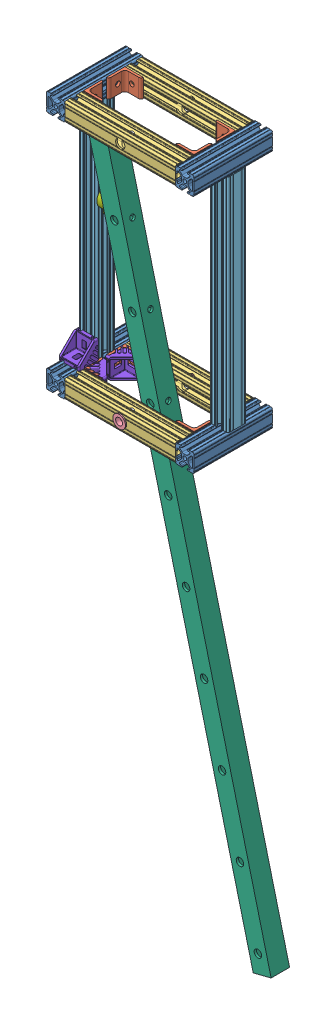
SolidWorks assembly assy_test_stand_8020, configuration Default. Lengths in mm.
Overall size (269.08 950.51 111.12).
28 component instances, 8 part files, 23 mates.
Components (placement in the parent):
- Base-1: Base [Default] at (-12.7 12.7 -79.4303) size (203.2 25.4 107.95)
  - prt_8020_1003_4.25in-1: prt_8020_1003_4.25in [Default] at origin size (25.4 25.4 107.95)
  - prt_8020_Lbracket_1x1-1: prt_8020_Lbracket_1x1 [Default] at (188.573 12.7 -96.9464) x (-1 0 0) z (0 -1 0) size (25.4 25.4 25.4)
  - prt_8020_Lbracket_1x1-2: prt_8020_Lbracket_1x1 [Default] at (39.7964 -12.7 -150.473) x (0 0 1) z (0 1 0) size (25.4 25.4 25.4)
  - prt_8020_Lbracket_1x1-3: prt_8020_Lbracket_1x1 [Default] at (188.573 -12.7 -99.9036) x (-1 0 0) z (0 1 0) size (25.4 25.4 25.4)
  - prt_8020_Lbracket_1x1-4: prt_8020_Lbracket_1x1 [Default] at (-10.773 -12.7 -96.9464) x (1 0 0) z (0 1 0) size (25.4 25.4 25.4)
  - prt_8020_1003_6in-1: prt_8020_1003_6in [Default] at (12.7 0 -139.7) x (0 0 1) z (-1 0 0) size (25.4 25.4 152.4)
  - prt_8020_1003_6in-2: prt_8020_1003_6in [Default] at (165.1 0 -57.15) x (0 0 -1) z (1 0 0) size (25.4 25.4 152.4)
  - prt_8020_1003_4.25in-2: prt_8020_1003_4.25in [Default] at (177.8 0 0) x (-1 0 0) z (0 0 1) size (25.4 25.4 107.95)
- Arms_risers-1: Arms_risers [Default] at (76.2 12.7 -245.0562) x (1 0 0) z (0 1 0) size (267.96 111.12 925.11)
  - prt_sleeve_bearing_0.375x.25-1: prt_sleeve_bearing_0.375x.25 [Default] at origin size (17.46 6.35 17.46)
  - prt_sleeve_bearing_0.375x.25-2: prt_sleeve_bearing_0.375x.25 [Default] at (0 -134.4017 0) x (0.923728 0 0.383049) z (0.383049 0 -0.923728) size (17.46 6.35 17.46)
  - prt_8020_1003_12in-1: prt_8020_1003_12in [Default] at (88.9 -61.6413 317.5) x (-1 0 0) z (0 0 1) size (25.4 25.4 304.8)
  - prt_8020_1003_12in-2: prt_8020_1003_12in [Default] at (-88.9 -64.5232 12.7) x (1 0 0) z (0 0 -1) size (25.4 25.4 304.8)
  - prt_arm-1: prt_arm [Default] at (-74.0887 -67.2009 290.7075) x (0.969025 0 0.246962) z (0.246962 0 -0.969025) size (25.4 25.4 923.8)
  - prt_load_cell-1: prt_load_cell [Default] at (-76.2 -64.5232 201.9224) x (0 1 0) z (0 0 -1) size (25.5 20.5 42.85)
- Base-2: Base [Default] at (-12.7 342.9 -79.4303) size (203.2 25.4 107.95)
  - prt_8020_1003_4.25in-1: prt_8020_1003_4.25in [Default] at origin size (25.4 25.4 107.95)
  - prt_8020_Lbracket_1x1-1: prt_8020_Lbracket_1x1 [Default] at (188.573 12.7 -96.9464) x (-1 0 0) z (0 -1 0) size (25.4 25.4 25.4)
  - prt_8020_Lbracket_1x1-2: prt_8020_Lbracket_1x1 [Default] at (39.7964 -12.7 -150.473) x (0 0 1) z (0 1 0) size (25.4 25.4 25.4)
  - prt_8020_Lbracket_1x1-3: prt_8020_Lbracket_1x1 [Default] at (188.573 -12.7 -99.9036) x (-1 0 0) z (0 1 0) size (25.4 25.4 25.4)
  - prt_8020_Lbracket_1x1-4: prt_8020_Lbracket_1x1 [Default] at (-10.773 -12.7 -96.9464) x (1 0 0) z (0 1 0) size (25.4 25.4 25.4)
  - prt_8020_1003_6in-1: prt_8020_1003_6in [Default] at (12.7 0 -139.7) x (0 0 1) z (-1 0 0) size (25.4 25.4 152.4)
  - prt_8020_1003_6in-2: prt_8020_1003_6in [Default] at (165.1 0 -57.15) x (0 0 -1) z (1 0 0) size (25.4 25.4 152.4)
  - prt_8020_1003_4.25in-2: prt_8020_1003_4.25in [Default] at (177.8 0 0) x (-1 0 0) z (0 0 1) size (25.4 25.4 107.95)
- brkt-1: brkt [Default] at (-11.4 25.4 -167.833) size (30.24 29.57 29.57)
- brkt-2: brkt [Default] at (0 11.4 -206.4303) x (0 1 0) z (1 0 0) size (30.24 29.57 29.57)
- brkt-3: brkt [Default] at (0 11.4 -149.2803) x (0 -1 0) z (1 0 0) size (30.24 29.57 29.57)
Mates (geometry in assembly coordinates):
- Coincident57: coincident: plane of Base-1/prt_8020_1003_4.25in-1 through (0 22.2504 -123.8803) normal (1 0 0); plane of assembly through (0 0 0) normal (1 0 0)
- Coincident58: coincident: plane of Base-1/prt_8020_1003_4.25in-1 through (-3.1496 0 -123.8803) normal (0 -1 0); plane of assembly through (0 0 0) normal (0 1 0)
- Coincident59: coincident: plane of Base-1/prt_8020_1003_4.25in-1 through (-25.4 7.3829 -123.8803) normal (-1 0 0); plane of Arms_risers-1/prt_8020_1003_12in-2 through (-25.4 25.4 -185.8501) normal (-1 0 0)
- Coincident60: coincident: plane of Base-1/prt_8020_1003_4.25in-1 through (-22.2504 25.4 -123.8803) normal (0 1 0); plane of Arms_risers-1/prt_8020_1003_12in-2 through (-19.1164 25.4 -190.0072) normal (0 -1 0)
- Concentric6: concentric: cylinder of Base-1/prt_8020_1003_6in-1 through (76.2 12.7 -206.4303) axis (0 0 -1) radius 6.35; cylinder of Arms_risers-1/prt_sleeve_bearing_0.375x.25-1 through (76.2 12.7 -190.0562) axis (0 0 1) radius 6.35
- Coincident61: coincident: plane of Base-1/prt_8020_1003_6in-1 through (0 7.3829 -231.8303) normal (0 0 -1); plane of Arms_risers-1/prt_sleeve_bearing_0.375x.25-1 through (84.9313 12.7 -231.8303) normal (0 0 1)
- Width3: width: plane of Base-1/prt_8020_1003_6in-1 through (0 22.2504 -206.4303) normal (0 0 1); plane of Base-1/prt_8020_1003_6in-2 through (152.4 22.2504 -149.2803) normal (0 0 -1); plane of Arms_risers-1/prt_arm-1 through (217.9484 -594.9143 -165.1553) normal (0 0 1); plane of Arms_risers-1/prt_arm-1 through (217.9484 -594.9143 -190.5553) normal (0 0 -1)
- Concentric7: concentric: cylinder of Base-1/prt_8020_1003_6in-2 through (76.2 12.7 -149.2803) axis (0 0 1) radius 6.35; cylinder of Arms_risers-1/prt_sleeve_bearing_0.375x.25-2 through (76.2 12.7 -165.6545) axis (0 0 -1) radius 6.35
- Coincident62: coincident: plane of Base-1/prt_8020_1003_6in-2 through (152.4 7.3829 -123.8803) normal (0 0 1); plane of Arms_risers-1/prt_sleeve_bearing_0.375x.25-2 through (84.2653 16.0445 -123.8803) normal (0 0 -1)
- Coincident63: coincident: plane of Base-1/prt_8020_1003_4.25in-2 through (171.4331 25.4 -123.8803) normal (0 1 0); plane of Arms_risers-1/prt_8020_1003_12in-1 through (171.5164 25.4 -192.8891) normal (0 -1 0)
- Coincident64: coincident: plane of Base-1/prt_8020_1003_4.25in-2 through (177.8 18.0171 -123.8803) normal (1 0 0); plane of Arms_risers-1/prt_8020_1003_12in-1 through (177.8 330.2 -188.7319) normal (1 0 0)
- Coincident65: coincident: plane of Base-1/prt_8020_1003_6in-2 through (152.4 7.3829 -123.8803) normal (0 0 1); plane of Base-2/prt_8020_1003_6in-2 through (152.4 337.5829 -123.8803) normal (0 0 1)
- Coincident66: coincident: plane of Base-1/prt_8020_1003_4.25in-2 through (177.8 18.0171 -123.8803) normal (1 0 0); plane of Base-2/prt_8020_1003_4.25in-2 through (177.8 348.2171 -123.8803) normal (1 0 0)
- Coincident67: coincident anti-aligned: plane of Arms_risers-1/prt_8020_1003_12in-1 through (171.5164 330.2 -192.8891) normal (0 1 0); plane of Base-2/prt_8020_1003_4.25in-2 through (158.7669 330.2 -123.8803) normal (0 -1 0)
- Coincident68: coincident anti-aligned: plane of Arms_risers-1/prt_8020_1003_12in-2 through (-22.2504 25.4 -167.833) normal (0 0 1); plane of brkt-1 through (-24.7 51.7 -167.833) normal (0 0 -1)
- Coincident69: coincident aligned: plane of Arms_risers-1/prt_8020_1003_12in-2 through (-25.4 25.4 -185.8501) normal (-1 0 0); plane of brkt-1 through (-25.4 26.1 -167.133) normal (-1 0 0)
- Coincident70: coincident: plane of Base-1/prt_8020_1003_4.25in-1 through (-22.2504 25.4 -123.8803) normal (0 1 0); plane of brkt-1 through (-24.7 25.4 -167.133) normal (0 -1 0)
- Coincident71: coincident: plane of Base-1/prt_8020_1003_6in-1 through (0 22.2504 -206.4303) normal (0 0 1); plane of brkt-2 through (0.7 -1.9 -206.4303) normal (0 0 -1)
- Coincident72: coincident: plane of Base-1/prt_8020_1003_4.25in-1 through (0 22.2504 -123.8803) normal (1 0 0); plane of brkt-2 through (0 -1.9 -180.1303) normal (-1 0 0)
- Coincident73: coincident: plane of Base-1/prt_8020_1003_4.25in-1 through (-6.3669 25.4 -123.8803) normal (0 1 0); plane of brkt-2 through (0.7 25.4 -205.7303) normal (0 1 0)
- Coincident75: coincident anti-aligned: plane of Base-1/prt_8020_1003_4.25in-1 through (0 22.2504 -123.8803) normal (1 0 0); plane of brkt-3 through (0 -1.9 -122.9803) normal (-1 0 0)
- Coincident76: coincident anti-aligned: plane of Base-1/prt_8020_1003_6in-2 through (152.4 22.2504 -149.2803) normal (0 0 -1); plane of brkt-3 through (0.7 -1.9 -149.2803) normal (0 0 -1)
- Coincident78: coincident aligned: plane of Base-1/prt_8020_1003_6in-2 through (152.4 25.4 -127.0299) normal (0 1 0); plane of brkt-3 through (0.7 25.4 -149.9803) normal (0 1 0)
